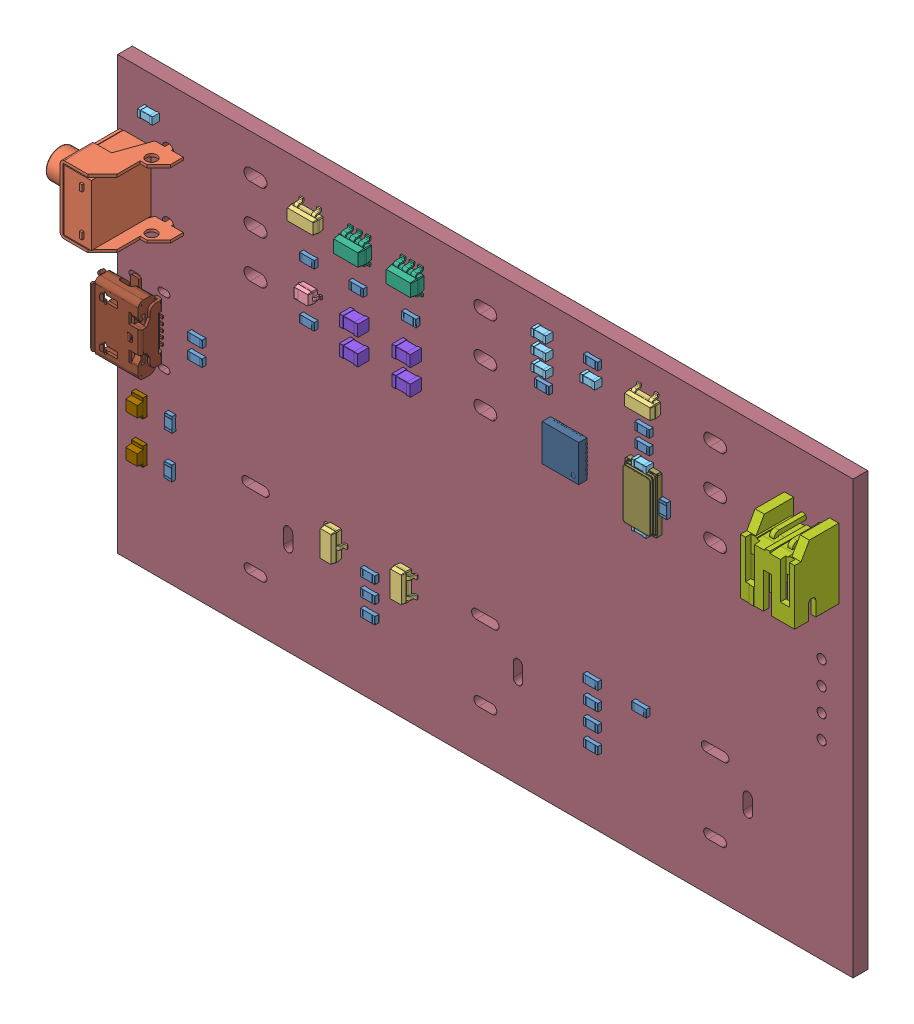
SolidWorks assembly ledTruckv1.1_new, configuration Default. Lengths in mm.
Overall size (82.71 47 11).
93 component instances, 13 part files, 0 mates.
Components (placement in the parent):
- R_0603_1608Metric-1: R_0603_1608Metric [Default] at (8.89 -22.225 1.65) x (-1 0 0) z (0 0 1) size (1.6 0.8 0.45)
  - SOLID-0-1: SOLID-0 [Default] at origin size (1.6 0.8 0.45)
- R_0603_1608Metric-2: R_0603_1608Metric [Default] at (8.89 -24.003 1.65) size (1.6 0.8 0.45)
  - SOLID-0-1: SOLID-0 [Default] at origin size (1.6 0.8 0.45)
- SW_Tactile_SPST_Angled_PTS645Vx58-2LFS-1: SW_Tactile_SPST_Angled_PTS645Vx58-2LFS [Default] at (3 -12 1.65) x (0 1 0) z (0 0 1) size (7.4 9.9 11)
  - SOLID-1-1: SOLID-1 [Default] at origin size (7.4 9.9 11)
- R_0603_1608Metric-3: R_0603_1608Metric [Default] at (26.416 -8.636 1.65) x (-1 0 0) z (0 0 1) size (1.6 0.8 0.45)
  - SOLID-0-1: SOLID-0 [Default] at origin size (1.6 0.8 0.45)
- R_0603_1608Metric-4: R_0603_1608Metric [Default] at (21.082 -14.478 1.65) size (1.6 0.8 0.45)
  - SOLID-0-1: SOLID-0 [Default] at origin size (1.6 0.8 0.45)
- R_0603_1608Metric-5: R_0603_1608Metric [Default] at (21.082 -8.636 1.65) x (-1 0 0) z (0 0 1) size (1.6 0.8 0.45)
  - SOLID-0-1: SOLID-0 [Default] at origin size (1.6 0.8 0.45)
- R_0603_1608Metric-6: R_0603_1608Metric [Default] at (27.686 -35.052 1.65) x (-1 0 0) z (0 0 1) size (1.6 0.8 0.45)
  - SOLID-0-1: SOLID-0 [Default] at origin size (1.6 0.8 0.45)
- SOT-23-1: SOT-23 [Default] at (21.082 -4.572 1.65) x (0 -1 0) z (0 0 1) size (2.5 3 1.2)
  - SOLID-2-1: SOLID-2 [Default] at origin size (2.5 3 1.2)
- SOT-23-2: SOT-23 [Default] at (31.496 -33.782 1.65) x (-1 0 0) z (0 0 1) size (2.5 3 1.2)
  - SOLID-2-1: SOLID-2 [Default] at origin size (2.5 3 1.2)
- SOT-23-3: SOT-23 [Default] at (23.876 -33.782 1.65) size (2.5 3 1.2)
  - SOLID-2-1: SOLID-2 [Default] at origin size (2.5 3 1.2)
- D_SOD-323-1: D_SOD-323 [Default] at (21.082 -11.684 1.65) size (2.5 1.25 1.1)
  - SOLID-3-1: SOLID-3 [Default] at origin size (2.5 1.25 1.1)
- C_0603_1608Metric-1: C_0603_1608Metric [Default] at (3.81 -3.556 1.65) size (1.6 0.8 0.8)
  - SOLID-4-1: SOLID-4 [Default] at origin size (1.6 0.8 0.8)
- R_0603_1608Metric-7: R_0603_1608Metric [Default] at (51.938 -2.799 1.65) size (1.6 0.8 0.45)
  - SOLID-0-1: SOLID-0 [Default] at origin size (1.6 0.8 0.45)
- SOT-23-4: SOT-23 [Default] at (57.78 -3.688 1.65) x (0 -1 0) z (0 0 1) size (2.5 3 1.2)
  - SOLID-2-1: SOLID-2 [Default] at origin size (2.5 3 1.2)
- C_0603_1608Metric-2: C_0603_1608Metric [Default] at (51.938 -4.45 1.65) x (-1 0 0) z (0 0 1) size (1.6 0.8 0.8)
  - SOLID-4-1: SOLID-4 [Default] at origin size (1.6 0.8 0.8)
- SOT-23-5-1: SOT-23-5 [Default] at (32.126 -4.704 1.65) x (0 -1 0) z (0 0 1) size (2.8 2.9 1.55)
  - SOLID-5-1: SOLID-5 [Default] at origin size (2.8 2.9 1.55)
- SOT-23-5-2: SOT-23-5 [Default] at (26.416 -4.699 1.65) x (0 -1 0) z (0 0 1) size (2.8 2.9 1.55)
  - SOLID-5-1: SOLID-5 [Default] at origin size (2.8 2.9 1.55)
- JST_PH_S2B-PH-K_1x02_P2.00mm_Horizontal-1: JST_PH_S2B-PH-K_1x02_P2.00mm_Horizontal [Default] at (74.544 -6.228 1.65) size (5.9 7.6 8.25)
  - SOLID-6-1: SOLID-6 [Default] at origin size (5.9 7.6 8.25)
- R_0603_1608Metric-8: R_0603_1608Metric [Default] at (57.1958 -32.8676 1.65) x (-1 0 0) z (0 0 1) size (1.6 0.8 0.45)
  - SOLID-0-1: SOLID-0 [Default] at origin size (1.6 0.8 0.45)
- R_0603_1608Metric-9: R_0603_1608Metric [Default] at (57.526 -8.006 1.65) size (1.6 0.8 0.45)
  - SOLID-0-1: SOLID-0 [Default] at origin size (1.6 0.8 0.45)
- R_0603_1608Metric-10: R_0603_1608Metric [Default] at (57.526 -6.355 1.65) x (-1 0 0) z (0 0 1) size (1.6 0.8 0.45)
  - SOLID-0-1: SOLID-0 [Default] at origin size (1.6 0.8 0.45)
- R_0603_1608Metric-11: R_0603_1608Metric [Default] at (5.969 -36.068 1.65) x (0 -1 0) z (0 0 1) size (1.6 0.8 0.45)
  - SOLID-0-1: SOLID-0 [Default] at origin size (1.6 0.8 0.45)
- R_0603_1608Metric-12: R_0603_1608Metric [Default] at (5.9944 -31.4706 1.65) x (0 1 0) z (0 0 1) size (1.6 0.8 0.45)
  - SOLID-0-1: SOLID-0 [Default] at origin size (1.6 0.8 0.45)
- R_0603_1608Metric-13: R_0603_1608Metric [Default] at (46.604 -7.752 1.65) size (1.6 0.8 0.45)
  - SOLID-0-1: SOLID-0 [Default] at origin size (1.6 0.8 0.45)
- R_0603_1608Metric-14: R_0603_1608Metric [Default] at (59.812 -12.705 1.65) x (0 1 0) z (0 0 1) size (1.6 0.8 0.45)
  - SOLID-0-1: SOLID-0 [Default] at origin size (1.6 0.8 0.45)
- R_0603_1608Metric-15: R_0603_1608Metric [Default] at (32.1514 -8.636 1.65) x (-1 0 0) z (0 0 1) size (1.6 0.8 0.45)
  - SOLID-0-1: SOLID-0 [Default] at origin size (1.6 0.8 0.45)
- R_0603_1608Metric-16: R_0603_1608Metric [Default] at (51.938 -38.994 1.65) x (-1 0 0) z (0 0 1) size (1.6 0.8 0.45)
  - SOLID-0-1: SOLID-0 [Default] at origin size (1.6 0.8 0.45)
- R_0603_1608Metric-17: R_0603_1608Metric [Default] at (51.938 -34.93 1.65) size (1.6 0.8 0.45)
  - SOLID-0-1: SOLID-0 [Default] at origin size (1.6 0.8 0.45)
- R_0603_1608Metric-18: R_0603_1608Metric [Default] at (27.686 -36.957 1.65) size (1.6 0.8 0.45)
  - SOLID-0-1: SOLID-0 [Default] at origin size (1.6 0.8 0.45)
- R_0603_1608Metric-19: R_0603_1608Metric [Default] at (51.938 -36.962 1.65) x (-1 0 0) z (0 0 1) size (1.6 0.8 0.45)
  - SOLID-0-1: SOLID-0 [Default] at origin size (1.6 0.8 0.45)
- R_0603_1608Metric-20: R_0603_1608Metric [Default] at (51.9176 -32.9184 1.65) x (-1 0 0) z (0 0 1) size (1.6 0.8 0.45)
  - SOLID-0-1: SOLID-0 [Default] at origin size (1.6 0.8 0.45)
- R_0603_1608Metric-21: R_0603_1608Metric [Default] at (27.686 -38.862 1.65) size (1.6 0.8 0.45)
  - SOLID-0-1: SOLID-0 [Default] at origin size (1.6 0.8 0.45)
- C_0805_2012Metric-1: C_0805_2012Metric [Default] at (26.416 -14.478 1.65) x (-1 0 0) z (0 0 1) size (2 1.25 1.25)
  - SOLID-7-1: SOLID-7 [Default] at origin size (2 1.25 1.25)
- C_0603_1608Metric-3: C_0603_1608Metric [Default] at (46.604 -6.101 1.65) x (-1 0 0) z (0 0 1) size (1.6 0.8 0.8)
  - SOLID-4-1: SOLID-4 [Default] at origin size (1.6 0.8 0.8)
- C_0805_2012Metric-2: C_0805_2012Metric [Default] at (32.126 -11.689 1.65) size (2 1.25 1.25)
  - SOLID-7-1: SOLID-7 [Default] at origin size (2 1.25 1.25)
- C_0603_1608Metric-4: C_0603_1608Metric [Default] at (46.604 -4.45 1.65) size (1.6 0.8 0.8)
  - SOLID-4-1: SOLID-4 [Default] at origin size (1.6 0.8 0.8)
- C_0603_1608Metric-5: C_0603_1608Metric [Default] at (46.604 -2.799 1.65) size (1.6 0.8 0.8)
  - SOLID-4-1: SOLID-4 [Default] at origin size (1.6 0.8 0.8)
- C_0805_2012Metric-3: C_0805_2012Metric [Default] at (26.416 -11.684 1.65) x (-1 0 0) z (0 0 1) size (2 1.25 1.25)
  - SOLID-7-1: SOLID-7 [Default] at origin size (2 1.25 1.25)
- C_0603_1608Metric-6: C_0603_1608Metric [Default] at (57.526 -9.657 1.65) size (1.6 0.8 0.8)
  - SOLID-4-1: SOLID-4 [Default] at origin size (1.6 0.8 0.8)
- C_0603_1608Metric-7: C_0603_1608Metric [Default] at (57.526 -15.626 1.65) size (1.6 0.8 0.8)
  - SOLID-4-1: SOLID-4 [Default] at origin size (1.6 0.8 0.8)
- C_0805_2012Metric-4: C_0805_2012Metric [Default] at (32.126 -14.478 1.65) size (2 1.25 1.25)
  - SOLID-7-1: SOLID-7 [Default] at origin size (2 1.25 1.25)
- LED_0805_2012Metric-1: LED_0805_2012Metric [Default] at (2.6589 -36 1.65) x (0 -1 0) z (0 0 1) size (2 1.25 1.1)
  - SOLID-8-1: SOLID-8 [Default] at origin size (2 1.25 1.1)
- LED_0805_2012Metric-2: LED_0805_2012Metric [Default] at (2.6589 -31.45 1.65) x (0 -1 0) z (0 0 1) size (2 1.25 1.1)
  - SOLID-8-1: SOLID-8 [Default] at origin size (2 1.25 1.1)
- QFN-32-1EP_4x4mm_P0.4mm_EP2.65x2.65mm-1: QFN-32-1EP_4x4mm_P0.4mm_EP2.65x2.65mm [Default] at (49.136 -12.5 1.65) x (-1 0 0) z (0 0 1) size (4 4 0.92)
  - SOLID-9-1: SOLID-9 [Default] at origin size (4 4 0.92)
- USB_Micro-B_Molex_47346-0001-1: USB_Micro-B_Molex_47346-0001 [Default] at (3.3873 -23.4924 1.65) x (0 -1 0) z (0 0 1) size (7.98 5.42 2.94)
  - SOLID-10-1: SOLID-10 [Default] at origin size (7.98 5.42 2.94)
- Crystal_SMD_0603-4Pin_6.0x3.5mm-1: Crystal_SMD_0603-4Pin_6.0x3.5mm [Default] at (57.526 -12.705 1.65) x (0 1 0) z (0 0 1) size (6 3.5 1.03)
  - SOLID-11-1: SOLID-11 [Default] at origin size (6 3.5 1.03)
- COMPOUND-1: COMPOUND [Default] at origin size (80 47 1.6)
